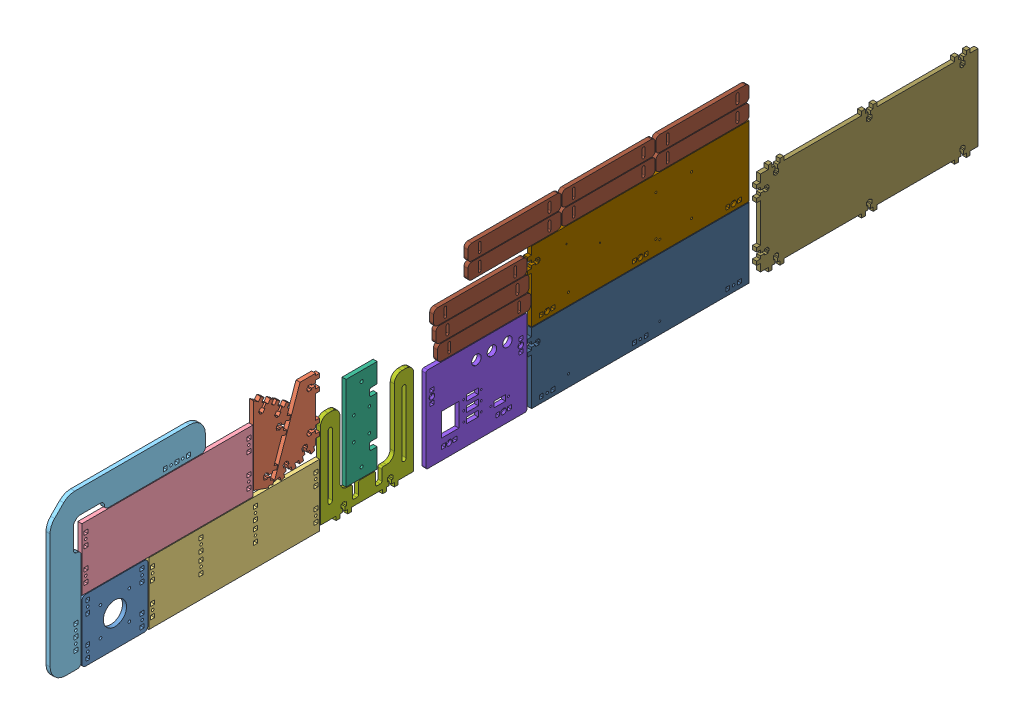
SolidWorks assembly Acrylic_4, configuration Default. Lengths in mm.
Overall size (6.6 374.78 1621.87).
21 component instances, 12 part files, 62 mates.
Components (placement in the parent):
- FACE, MOTOR MOUNT-1: FACE, MOTOR MOUNT [LASER CUT] at origin size (6.6 101.7 108.05)
- SIDE, MOTOR MOUNT-1: SIDE, MOTOR MOUNT [LASER CUT] at (0 56.0967 -260.5881) x (-1 0 0) z (0 -0.707107 -0.707107) size (6.6 134.94 94.07)
- SIDE, MOTOR MOUNT-2: SIDE, MOTOR MOUNT [LASER CUT] at (6.604 187.4665 -226.7966) x (1 0 0) z (0 0.432592 -0.90159) size (6.6 134.94 94.07)
- LOWER OUTFEED FRONT RIB, FRAME-1: LOWER OUTFEED FRONT RIB, FRAME [LASER CUT] at (0 50.8 -195.0466) size (6.6 101.7 279.5)
- LOWER INFEED FRONT RIB, FRAME-1: LOWER INFEED FRONT RIB, FRAME [LASER CUT] at (0 153.7716 -85.725) size (6.6 101.7 279.5)
- SIDE PADDLE, SADDLE-2: SIDE PADDLE, SADDLE [Default] at (0 155.0924 55.2958) x (0 0.707107 -0.707107) z (1 0 0) size (338.17 191.85 6.6)
- LINK, SADDLE-1: LINK, SADDLE [Default] at (0 65.9892 -403.3774) x (0 -1 0) z (0 0 1) size (152.4 6.6 50.8)
- LOWER PADDLE SLIDE, SADDLE-1: LOWER PADDLE SLIDE, SADDLE [Default] at (0 -43.2308 -412.2674) x (0 0 1) z (0 1 0) size (152.4 6.6 158.75)
- FRONT, ELECTRONICS SLIDE-1: FRONT, ELECTRONICS SLIDE [LASER CUT] at (0 19.05 -590.9818) size (6.6 139.8 165.2)
- SIDE INFEED, ELECTRONICS SLIDE-1: SIDE INFEED, ELECTRONICS SLIDE [LASER CUT] at (0 64.8716 -859.0534) size (6.6 114.4 362.05)
- SIDE OUTFEED, ELECTRONICS SLIDE-1: SIDE OUTFEED, ELECTRONICS SLIDE [LASER CUT] at (0 -50.8 -859.0534) size (6.6 114.4 362.05)
- SPACER, BASE-1: SPACER, BASE [Default] at (0 102.9208 -603.7326) x (0 -1 0) z (0 0 1) size (25.4 6.6 152.4)
- SPACER, BASE-2: SPACER, BASE [Default] at (0 129.5908 -600.9386) x (0 -1 0) z (0 0 1) size (25.4 6.6 152.4)
- SPACER, BASE-3: SPACER, BASE [Default] at (0 156.2608 -597.3826) x (0 -1 0) z (0 0 1) size (25.4 6.6 152.4)
- SPACER, BASE-5: SPACER, BASE [Default] at (0 193.1924 -960.7042) x (0 -1 0) z (0 0 1) size (25.4 6.6 152.4)
- SPACER, BASE-6: SPACER, BASE [Default] at (0 219.8624 -960.7042) x (0 -1 0) z (0 0 1) size (25.4 6.6 152.4)
- SPACER, BASE-8: SPACER, BASE [Default] at (0 193.1924 -807.0342) x (0 -1 0) z (0 0 1) size (25.4 6.6 152.4)
- SPACER, BASE-9: SPACER, BASE [Default] at (0 219.8624 -807.0342) x (0 -1 0) z (0 0 1) size (25.4 6.6 152.4)
- SPACER, BASE-10: SPACER, BASE [Default] at (0 193.1924 -653.3642) x (0 -1 0) z (0 0 1) size (25.4 6.6 152.4)
- BASE, ELECTRONICS SLIDE-1: BASE, ELECTRONICS SLIDE [Default] at (0 24.8976 -1233.2894) x (0 -1 0) z (0 0 1) size (151.38 6.6 361.95)
- SPACER, BASE-11: SPACER, BASE [Default] at (0 219.8624 -653.3642) x (0 -1 0) z (0 0 1) size (25.4 6.6 152.4)
Mates (geometry in assembly coordinates):
- Coincident1: coincident aligned: plane of FACE, MOTOR MOUNT-1 through (0 0 0) normal (0 0 1); plane of assembly through (0 0 0) normal (0 0 1)
- Coincident2: coincident aligned: plane of FACE, MOTOR MOUNT-1 through (0 0 0) normal (0 1 0); plane of assembly through (0 0 0) normal (0 1 0)
- Coincident3: coincident aligned: plane of FACE, MOTOR MOUNT-1 through (0 0 0) normal (1 0 0); plane of assembly through (0 0 0) normal (1 0 0)
- Coincident5: coincident aligned: plane of FACE, MOTOR MOUNT-1 through (6.604 0 0) normal (1 0 0); plane of SIDE, MOTOR MOUNT-2 through (6.604 187.4665 -226.7966) normal (1 0 0)
- Coincident8: coincident aligned: plane of FACE, MOTOR MOUNT-1 through (6.604 0 0) normal (1 0 0); plane of LOWER OUTFEED FRONT RIB, FRAME-1 through (6.604 50.8 -195.0466) normal (1 0 0)
- Coincident9: coincident aligned: plane of FACE, MOTOR MOUNT-1 through (6.604 -50.8508 53.975) normal (0 -1 0); plane of LOWER OUTFEED FRONT RIB, FRAME-1 through (6.604 -50.8508 -55.3466) normal (0 -1 0)
- Distance2: distance = 1.27 mm anti-aligned: plane of FACE, MOTOR MOUNT-1 through (6.604 50.8 -54.0258) normal (0 0 -1); plane of LOWER OUTFEED FRONT RIB, FRAME-1 through (6.604 50.8 -55.2958) normal (0 0 1)
- Distance3: distance = 1.27 mm anti-aligned: plane of LOWER OUTFEED FRONT RIB, FRAME-1 through (6.604 50.8508 -55.3466) normal (0 1 0); plane of LOWER INFEED FRONT RIB, FRAME-1 through (6.604 52.1208 53.975) normal (0 -1 0)
- Coincident12: coincident aligned: plane of LOWER OUTFEED FRONT RIB, FRAME-1 through (6.604 50.8 -195.0466) normal (1 0 0); plane of LOWER INFEED FRONT RIB, FRAME-1 through (6.604 153.7716 -85.725) normal (1 0 0)
- Coincident13: coincident aligned: plane of FACE, MOTOR MOUNT-1 through (6.604 50.8 54.0258) normal (0 0 1); plane of LOWER INFEED FRONT RIB, FRAME-1 through (6.604 153.7716 54.0258) normal (0 0 1)
- Coincident15: coincident aligned: plane of LOWER OUTFEED FRONT RIB, FRAME-1 through (6.604 50.8 -195.0466) normal (1 0 0); plane of LINK, SADDLE-1 through (6.604 65.9892 -403.3774) normal (1 0 0)
- Coincident16: coincident aligned: plane of LOWER OUTFEED FRONT RIB, FRAME-1 through (6.604 50.8 -195.0466) normal (1 0 0); plane of SIDE PADDLE, SADDLE-2 through (6.604 155.0924 55.2958) normal (1 0 0)
- Coincident17: coincident aligned: plane of LOWER OUTFEED FRONT RIB, FRAME-1 through (6.604 50.8 -195.0466) normal (1 0 0); plane of LOWER PADDLE SLIDE, SADDLE-1 through (6.604 -43.2308 -412.2674) normal (1 0 0)
- Coincident18: coincident aligned: plane of LOWER OUTFEED FRONT RIB, FRAME-1 through (6.604 50.8 -195.0466) normal (1 0 0); plane of LINK, SADDLE-1 through (6.604 65.9892 -403.3774) normal (1 0 0)
- Distance4: distance = 1.27 mm anti-aligned: plane of LOWER INFEED FRONT RIB, FRAME-1 through (6.604 153.8224 53.975) normal (0 1 0); plane of SIDE PADDLE, SADDLE-2 through (6.604 155.0924 55.2958) normal (0 -1 0)
- Distance5: distance = 1.27 mm anti-aligned: plane of LOWER INFEED FRONT RIB, FRAME-1 through (6.604 153.7716 54.0258) normal (0 0 1); plane of SIDE PADDLE, SADDLE-2 through (6.604 -48.1076 55.2958) normal (0 0 -1)
- Distance6: distance = 1.27 mm anti-aligned: plane of LOWER PADDLE SLIDE, SADDLE-1 through (6.604 -43.2308 -336.0674) normal (0 0 1); plane of LOWER OUTFEED FRONT RIB, FRAME-1 through (6.604 50.8 -334.7974) normal (0 0 -1)
- Distance7: distance = 1.27 mm aligned: plane of LOWER OUTFEED FRONT RIB, FRAME-1 through (6.604 -50.8508 -55.3466) normal (0 -1 0); plane of LOWER PADDLE SLIDE, SADDLE-1 through (-8.9803 -49.5808 -367.8174) normal (0 -1 0)
- Distance8: distance = 1.27 mm anti-aligned: plane of SIDE, MOTOR MOUNT-2 through (0 187.4665 -226.7458) normal (0 0 1); plane of LOWER INFEED FRONT RIB, FRAME-1 through (6.604 153.7716 -225.4758) normal (0 0 -1)
- Distance9: distance = 1.27 mm: plane of LOWER OUTFEED FRONT RIB, FRAME-1 through (6.604 50.8508 -55.3466) normal (0 1 0); line of SIDE, MOTOR MOUNT-2 through (0 52.1208 -250.7903) axis (1 0 0)
- Coincident27: coincident aligned: plane of SIDE, MOTOR MOUNT-1 through (6.604 56.0967 -260.5881) normal (1 0 0); plane of LOWER OUTFEED FRONT RIB, FRAME-1 through (6.604 50.8 -195.0466) normal (1 0 0)
- Distance12: distance = 1.27 mm anti-aligned: plane of SIDE, MOTOR MOUNT-1 through (6.604 56.1136 -260.5402) normal (0 0.331631 0.943409); plane of SIDE, MOTOR MOUNT-2 through (-12.954 130.8524 -285.4665) normal (0 -0.331631 -0.943409)
- Distance13: distance = 1.27 mm: line of SIDE, MOTOR MOUNT-1 through (6.604 52.1208 -271.4618) axis (-1 0 0); plane of LOWER OUTFEED FRONT RIB, FRAME-1 through (6.604 50.8508 -55.3466) normal (0 1 0)
- Distance14: distance = 1.27 mm anti-aligned: plane of LOWER PADDLE SLIDE, SADDLE-1 through (6.604 -11.4808 -456.7174) normal (0 1 0); plane of LINK, SADDLE-1 through (6.604 -10.2108 -428.7774) normal (0 -1 0)
- Distance15: distance = 10.16 mm anti-aligned: plane of LINK, SADDLE-1 through (6.604 142.1892 -377.9774) normal (0 0 1); plane of LOWER PADDLE SLIDE, SADDLE-1 through (6.604 109.1692 -367.8174) normal (0 0 -1)
- Coincident34: coincident aligned: plane of LOWER OUTFEED FRONT RIB, FRAME-1 through (6.604 50.8 -195.0466) normal (1 0 0); plane of SIDE INFEED, ELECTRONICS SLIDE-1 through (6.604 64.8716 -859.0534) normal (1 0 0)
- Coincident35: coincident aligned: plane of LOWER OUTFEED FRONT RIB, FRAME-1 through (6.604 50.8 -195.0466) normal (1 0 0); plane of SIDE OUTFEED, ELECTRONICS SLIDE-1 through (6.604 -50.8 -859.0534) normal (1 0 0)
- Coincident36: coincident aligned: plane of LOWER OUTFEED FRONT RIB, FRAME-1 through (6.604 50.8 -195.0466) normal (1 0 0); plane of FRONT, ELECTRONICS SLIDE-1 through (6.604 19.05 -590.9818) normal (1 0 0)
- Distance16: distance = 1143 mm anti-aligned: plane of SIDE OUTFEED, ELECTRONICS SLIDE-1 through (6.604 63.5 -1036.9042) normal (0 0 -1); plane of SIDE PADDLE, SADDLE-2 through (6.604 176.1344 106.0958) normal (0 0 1)
- Coincident38: coincident aligned: plane of LOWER OUTFEED FRONT RIB, FRAME-1 through (6.604 -50.8508 -55.3466) normal (0 -1 0); plane of SIDE OUTFEED, ELECTRONICS SLIDE-1 through (6.604 -50.8508 -681.2534) normal (0 -1 0)
- Coincident39: coincident aligned: plane of FRONT, ELECTRONICS SLIDE-1 through (6.604 -50.8508 -508.4318) normal (0 -1 0); plane of SIDE OUTFEED, ELECTRONICS SLIDE-1 through (6.604 -50.8508 -681.2534) normal (0 -1 0)
- Distance17: distance = 1.27 mm anti-aligned: plane of SIDE OUTFEED, ELECTRONICS SLIDE-1 through (15.5843 31.75 -674.8526) normal (0 0 1); plane of FRONT, ELECTRONICS SLIDE-1 through (6.604 88.9 -673.5826) normal (0 0 -1)
- Coincident41: coincident aligned: plane of SIDE INFEED, ELECTRONICS SLIDE-1 through (6.604 179.1716 -1036.9042) normal (0 0 -1); plane of SIDE OUTFEED, ELECTRONICS SLIDE-1 through (6.604 63.5 -1036.9042) normal (0 0 -1)
- Distance18: distance = 1.27 mm anti-aligned: plane of SIDE OUTFEED, ELECTRONICS SLIDE-1 through (6.604 63.5508 -681.2534) normal (0 1 0); plane of SIDE INFEED, ELECTRONICS SLIDE-1 through (6.604 64.8208 -681.2534) normal (0 -1 0)
- Coincident42: coincident aligned: plane of FRONT, ELECTRONICS SLIDE-1 through (6.604 19.05 -590.9818) normal (1 0 0); plane of SPACER, BASE-1 through (6.604 102.9208 -603.7326) normal (1 0 0)
- Distance19: distance = 1.27 mm anti-aligned: plane of FRONT, ELECTRONICS SLIDE-1 through (6.604 88.9508 -508.4318) normal (0 1 0); plane of SPACER, BASE-1 through (6.604 90.2208 -679.9326) normal (0 -1 0)
- Distance20: distance = 1.27 mm anti-aligned: plane of SIDE INFEED, ELECTRONICS SLIDE-1 through (6.604 179.1716 -681.2026) normal (0 0 1); plane of SPACER, BASE-1 through (6.604 115.6208 -679.9326) normal (0 0 -1)
- Coincident45: coincident aligned: plane of SPACER, BASE-1 through (6.604 102.9208 -603.7326) normal (1 0 0); plane of SPACER, BASE-2 through (6.604 129.5908 -600.9386) normal (1 0 0)
- Distance21: distance = 1.27 mm anti-aligned: plane of SPACER, BASE-1 through (6.604 115.6208 -679.9326) normal (0 1 0); plane of SPACER, BASE-2 through (6.604 116.8908 -677.1386) normal (0 -1 0)
- Distance22: distance = 4.064 mm anti-aligned: plane of SIDE INFEED, ELECTRONICS SLIDE-1 through (6.604 179.1716 -681.2026) normal (0 0 1); plane of SPACER, BASE-2 through (6.604 142.2908 -677.1386) normal (0 0 -1)
- Coincident46: coincident aligned: plane of SIDE OUTFEED, ELECTRONICS SLIDE-1 through (6.604 -50.8 -859.0534) normal (1 0 0); plane of SPACER, BASE-3 through (6.604 156.2608 -597.3826) normal (1 0 0)
- Distance23: distance = 1.27 mm anti-aligned: plane of SPACER, BASE-2 through (6.604 142.2908 -677.1386) normal (0 1 0); plane of SPACER, BASE-3 through (6.604 143.5608 -673.5826) normal (0 -1 0)
- Distance24: distance = 1.27 mm anti-aligned: plane of SIDE INFEED, ELECTRONICS SLIDE-1 through (15.5843 160.1216 -674.8526) normal (0 0 1); plane of SPACER, BASE-3 through (6.604 168.9608 -673.5826) normal (0 0 -1)
- Coincident48: coincident aligned: plane of SIDE INFEED, ELECTRONICS SLIDE-1 through (6.604 64.8716 -859.0534) normal (1 0 0); plane of SPACER, BASE-5 through (6.604 193.1924 -960.7042) normal (1 0 0)
- Distance27: distance = 1.27 mm anti-aligned: plane of SIDE INFEED, ELECTRONICS SLIDE-1 through (6.604 179.2224 -681.2534) normal (0 1 0); plane of SPACER, BASE-5 through (6.604 180.4924 -1036.9042) normal (0 -1 0)
- Coincident50: coincident aligned: plane of SIDE INFEED, ELECTRONICS SLIDE-1 through (6.604 179.1716 -1036.9042) normal (0 0 -1); plane of SPACER, BASE-5 through (6.604 205.8924 -1036.9042) normal (0 0 -1)
- Coincident51: coincident aligned: plane of SIDE OUTFEED, ELECTRONICS SLIDE-1 through (6.604 -50.8 -859.0534) normal (1 0 0); plane of SPACER, BASE-6 through (6.604 219.8624 -960.7042) normal (1 0 0)
- Distance28: distance = 1.27 mm anti-aligned: plane of SPACER, BASE-5 through (6.604 205.8924 -1036.9042) normal (0 1 0); plane of SPACER, BASE-6 through (6.604 207.1624 -1036.9042) normal (0 -1 0)
- Coincident52: coincident aligned: plane of SPACER, BASE-5 through (6.604 205.8924 -1036.9042) normal (0 0 -1); plane of SPACER, BASE-6 through (6.604 232.5624 -1036.9042) normal (0 0 -1)
- Coincident55: coincident aligned: plane of SIDE INFEED, ELECTRONICS SLIDE-1 through (6.604 64.8716 -859.0534) normal (1 0 0); plane of SPACER, BASE-8 through (6.604 193.1924 -807.0342) normal (1 0 0)
- Distance30: distance = 1.27 mm anti-aligned: plane of SIDE INFEED, ELECTRONICS SLIDE-1 through (6.604 179.2224 -681.2534) normal (0 1 0); plane of SPACER, BASE-8 through (6.604 180.4924 -883.2342) normal (0 -1 0)
- Distance31: distance = 1.27 mm anti-aligned: plane of SPACER, BASE-5 through (6.604 205.8924 -884.5042) normal (0 0 1); plane of SPACER, BASE-8 through (6.604 205.8924 -883.2342) normal (0 0 -1)
- Coincident56: coincident aligned: plane of SPACER, BASE-8 through (6.604 193.1924 -807.0342) normal (1 0 0); plane of SPACER, BASE-9 through (6.604 219.8624 -807.0342) normal (1 0 0)
- Distance32: distance = 1.27 mm anti-aligned: plane of SPACER, BASE-8 through (6.604 205.8924 -883.2342) normal (0 1 0); plane of SPACER, BASE-9 through (6.604 207.1624 -883.2342) normal (0 -1 0)
- Distance33: distance = 1.27 mm anti-aligned: plane of SPACER, BASE-6 through (6.604 232.5624 -884.5042) normal (0 0 1); plane of SPACER, BASE-9 through (6.604 232.5624 -883.2342) normal (0 0 -1)
- Coincident57: coincident aligned: plane of SIDE INFEED, ELECTRONICS SLIDE-1 through (6.604 64.8716 -859.0534) normal (1 0 0); plane of SPACER, BASE-10 through (6.604 193.1924 -653.3642) normal (1 0 0)
- Distance34: distance = 1.27 mm anti-aligned: plane of SIDE INFEED, ELECTRONICS SLIDE-1 through (6.604 179.2224 -681.2534) normal (0 1 0); plane of SPACER, BASE-10 through (6.604 180.4924 -729.5642) normal (0 -1 0)
- Distance35: distance = 1.27 mm anti-aligned: plane of SPACER, BASE-8 through (6.604 205.8924 -730.8342) normal (0 0 1); plane of SPACER, BASE-10 through (6.604 205.8924 -729.5642) normal (0 0 -1)
- Coincident58: coincident aligned: plane of SIDE INFEED, ELECTRONICS SLIDE-1 through (6.604 64.8716 -859.0534) normal (1 0 0); plane of BASE, ELECTRONICS SLIDE-1 through (6.604 24.8976 -1233.2894) normal (1 0 0)
- Coincident59: coincident aligned: plane of SPACER, BASE-8 through (6.604 193.1924 -807.0342) normal (1 0 0); plane of SPACER, BASE-11 through (6.604 219.8624 -653.3642) normal (1 0 0)
- Distance36: distance = 1.27 mm anti-aligned: plane of SPACER, BASE-10 through (6.604 205.8924 -729.5642) normal (0 1 0); plane of SPACER, BASE-11 through (6.604 207.1624 -729.5642) normal (0 -1 0)
- Distance37: distance = 1.27 mm anti-aligned: plane of SPACER, BASE-9 through (6.604 232.5624 -730.8342) normal (0 0 1); plane of SPACER, BASE-11 through (6.604 232.5624 -729.5642) normal (0 0 -1)
